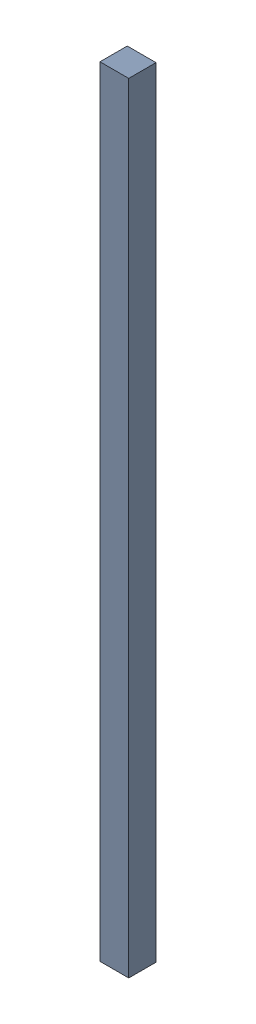
SolidWorks assembly PCB2.step, configuration Default. Lengths in mm.
Overall size (0.47 12.7 0.45).
4 component instances, 2 part files, 0 mates.
Components (placement in the parent):
- Free-Models-2.step-1: Free-Models-2.step [Default] at origin size (0.47 12.7 0.45)
  - 790454240.step-1: 790454240.step [Default] at (0 -6.35 -0.35) size (0.47 12.7 0.45)
    - Extruded-45.step-1: Extruded-45.step [Default] at origin size (0.47 12.7 0.45)
- Board-46.step-1: Board-46.step [Default] at (0 0 -0.2083) size (0.27 0.27 0.21)
